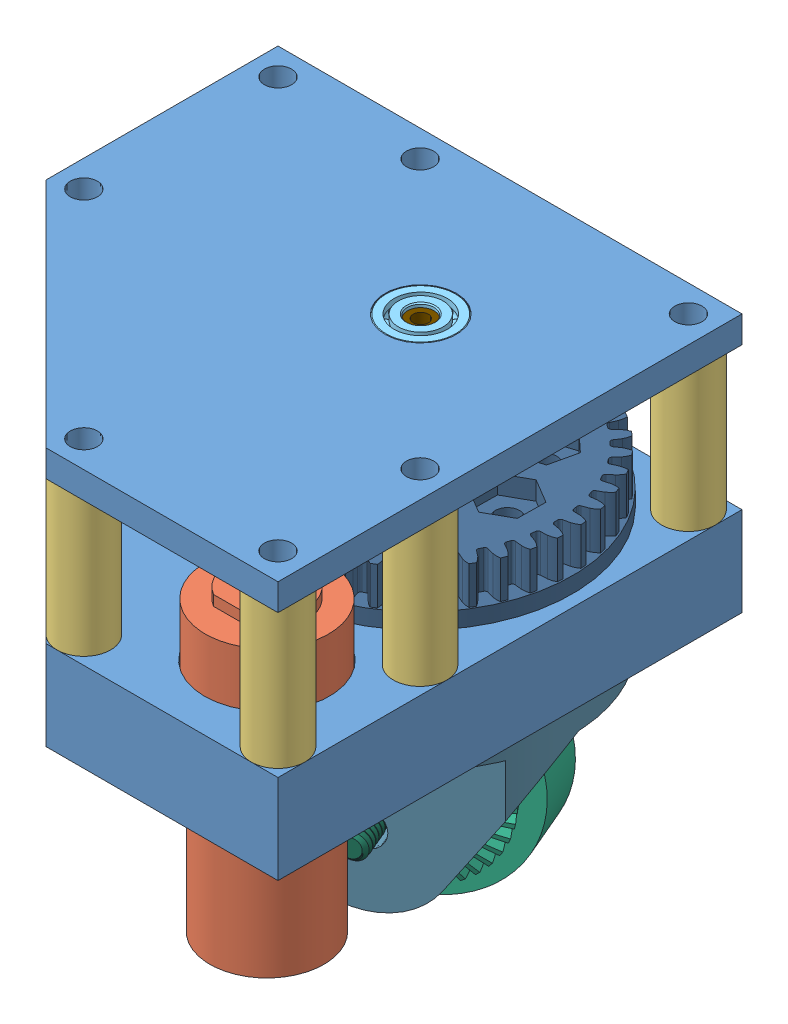
SolidWorks assembly Coaxial-Swerve Test Assem, configuration Default. Lengths in mm.
Overall size (91.34 93.34 91.31).
79 component instances, 21 part files, 31 mates.
Components (placement in the parent):
- Coaxial-Swerve test-1: Coaxial-Swerve test [Default] at origin size (78.17 85.72 76.44) (hidden)
- Middle Container Block-1: Middle Container Block [Default] at (0 47.625 0) size (82.55 15.88 82.55)
- brushless drive motor-1: brushless drive motor [Default] at (9.525 13.7795 36.8902) size (21.95 65.35 21.95)
- brushless drive motor-2: brushless drive motor [Default] at (-36.8902 4.2545 -9.525) size (21.95 65.35 21.95)
- RB Standoff-1: RB Standoff [1000L] at (23.8125 68.2625 -23.8125) size (9.53 25.4 9.53)
- Middle Container Block-2: Middle Container Block [Top] at (0 50.8 0) size (82.55 4.76 82.55)
- RB Standoff-2: RB Standoff [1000L] at (23.8125 68.2625 23.9339) x (0.982082 0 -0.188455) z (0.188455 0 0.982082) size (9.53 25.4 9.53)
- RB Standoff-3: RB Standoff [1000L] at (23.8125 68.2625 49.2125) x (0.918365 0 -0.395734) z (0.395734 0 0.918365) size (9.53 25.4 9.53)
- RB Standoff-4: RB Standoff [1000L] at (-10.7273 68.2625 49.2125) x (0.8 0 -0.6) z (0.6 0 0.8) size (9.53 25.4 9.53)
- RB Standoff-5: RB Standoff [1000L] at (-49.2125 68.2625 10.7273) x (0.63358 0 -0.773678) z (0.773678 0 0.63358) size (9.53 25.4 9.53)
- RB Standoff-6: RB Standoff [1000L] at (-49.2125 68.2625 -23.8125) x (0.443629 0 -0.896211) z (0.896211 0 0.443629) size (9.53 25.4 9.53)
- RB Standoff-7: RB Standoff [1000L] at (-23.9339 68.2625 -23.8125) x (0.263225 0 -0.964735) z (0.964735 0 0.263225) size (9.53 25.4 9.53)
- Coaxial-Swerve Inner Modual Test Assem-1: Coaxial-Swerve Inner Modual Test Assem [Default] at (0 19.05 0) x (-0.393232 0 -0.919439) z (0.919439 0 -0.393232) size (53.98 92.63 53.98)
  - Coaxial-Swerve test-1: Coaxial-Swerve test [Default] at origin size (78.17 85.72 76.44) (hidden)
  - 57155K352_Stainless Steel Ball Bearing-1: 57155K352_Stainless Steel Ball Bearing [57155K352] at (-12.7 7.6375 0) x (1 0 0) z (0 -1 0) size (7.94 7.94 2.78)
  - 60355K502_Ball Bearing-1: 60355K502_Ball Bearing [60355K502] at (-12.7 39.0049 0) x (1 0 0) z (0 -1 0) size (12.7 12.7 3.97)
  - wheel bevel gear-2: wheel bevel gear [Hub and Gear] at (-5.2165 0 0) x (-1 0 0) z (0 -0.800175 0.599767) size (17.39 32.09 32.09)
  - wheel bevel pinion-2: wheel bevel pinion [Inch - Straight bevel pinion 32DP15PT 40GT 20PA .25FW ---15O3H.063MD0.1875N] at (-12.7 16.1735 0) x (0 -1 0) z (0.960661 0 -0.277724) size (7.15 13.7 13.78)
  - Inside Powered Gear-1: Inside Powered Gear [Default] at (-12.7 28.575 0) x (-0.277724 0 -0.960661) z (0 1 0) size (14.29 14.36 13.21)
  - Inside Powering Pinion-1: Inside Powering Pinion [Default] at (0 28.575 0) x (-0.686506 0 0.727124) z (0 1 0) size (14.29 14.36 24.33)
  - Swivel Base Gear-1: Swivel Base Gear [Default] at (0 41.783 0) x (0 0 1) z (0 1 0) size (53.98 53.98 14.13)
  - 60355K503_Ball Bearing (1)-1: 60355K503_Ball Bearing (1) [60355K503] at (0 44.0563 0) x (1 0 0) z (0 -1 0) size (15.88 15.88 4.98)
  - Above Driven Pully-1: Above Driven Pully [Default] at (0 56.515 0) x (0.972961 0 0.23097) z (-0.23097 0 0.972961) size (28.62 10.01 28.62)
  - 9613K15_Wear-Resistant Nylon Balls-1: 9613K15_Wear-Resistant Nylon Balls [9613K15] at (-23.1902 20.3835 0) x (0.958311 0.024656 0.284661) z (-0.285108 0.016955 0.958346) size (4.76 4.76 4.76)
  - 9613K15_Wear-Resistant Nylon Balls-2: 9613K15_Wear-Resistant Nylon Balls [9613K15] at (-23.1902 36.7665 0) size (4.76 4.76 4.76)
  - 9613K15_Wear-Resistant Nylon Balls-3: 9613K15_Wear-Resistant Nylon Balls [9613K15] at (-22.0552 36.7665 7.1662) x (0.951057 0 -0.309017) z (0.309017 0 0.951057) size (4.76 4.76 4.76)
  - 9613K15_Wear-Resistant Nylon Balls-4: 9613K15_Wear-Resistant Nylon Balls [9613K15] at (-18.7613 36.7665 13.6309) x (0.809017 0 -0.587785) z (0.587785 0 0.809017) size (4.76 4.76 4.76)
  - 9613K15_Wear-Resistant Nylon Balls-5: 9613K15_Wear-Resistant Nylon Balls [9613K15] at (-13.6309 36.7665 18.7613) x (0.587785 0 -0.809017) z (0.809017 0 0.587785) size (4.76 4.76 4.76)
  - 9613K15_Wear-Resistant Nylon Balls-6: 9613K15_Wear-Resistant Nylon Balls [9613K15] at (-7.1662 36.7665 22.0552) x (0.309017 0 -0.951057) z (0.951057 0 0.309017) size (4.76 4.76 4.76)
  - 9613K15_Wear-Resistant Nylon Balls-7: 9613K15_Wear-Resistant Nylon Balls [9613K15] at (0 36.7665 23.1902) x (0 0 -1) z (1 0 0) size (4.76 4.76 4.76)
  - 9613K15_Wear-Resistant Nylon Balls-8: 9613K15_Wear-Resistant Nylon Balls [9613K15] at (7.1662 36.7665 22.0552) x (-0.309017 0 -0.951057) z (0.951057 0 -0.309017) size (4.76 4.76 4.76)
  - 9613K15_Wear-Resistant Nylon Balls-9: 9613K15_Wear-Resistant Nylon Balls [9613K15] at (13.6309 36.7665 18.7613) x (-0.587785 0 -0.809017) z (0.809017 0 -0.587785) size (4.76 4.76 4.76)
  - 9613K15_Wear-Resistant Nylon Balls-10: 9613K15_Wear-Resistant Nylon Balls [9613K15] at (18.7613 36.7665 13.6309) x (-0.809017 0 -0.587785) z (0.587785 0 -0.809017) size (4.76 4.76 4.76)
  - 9613K15_Wear-Resistant Nylon Balls-11: 9613K15_Wear-Resistant Nylon Balls [9613K15] at (22.0552 36.7665 7.1662) x (-0.951057 0 -0.309017) z (0.309017 0 -0.951057) size (4.76 4.76 4.76)
  - 9613K15_Wear-Resistant Nylon Balls-12: 9613K15_Wear-Resistant Nylon Balls [9613K15] at (23.1902 36.7665 0) x (-1 0 0) z (0 0 -1) size (4.76 4.76 4.76)
  - 9613K15_Wear-Resistant Nylon Balls-13: 9613K15_Wear-Resistant Nylon Balls [9613K15] at (22.0552 36.7665 -7.1662) x (-0.951057 0 0.309017) z (-0.309017 0 -0.951057) size (4.76 4.76 4.76)
  - 9613K15_Wear-Resistant Nylon Balls-14: 9613K15_Wear-Resistant Nylon Balls [9613K15] at (18.7613 36.7665 -13.6309) x (-0.809017 0 0.587785) z (-0.587785 0 -0.809017) size (4.76 4.76 4.76)
  - 9613K15_Wear-Resistant Nylon Balls-15: 9613K15_Wear-Resistant Nylon Balls [9613K15] at (13.6309 36.7665 -18.7613) x (-0.587785 0 0.809017) z (-0.809017 0 -0.587785) size (4.76 4.76 4.76)
  - 9613K15_Wear-Resistant Nylon Balls-16: 9613K15_Wear-Resistant Nylon Balls [9613K15] at (7.1662 36.7665 -22.0552) x (-0.309017 0 0.951057) z (-0.951057 0 -0.309017) size (4.76 4.76 4.76)
  - 9613K15_Wear-Resistant Nylon Balls-17: 9613K15_Wear-Resistant Nylon Balls [9613K15] at (0 36.7665 -23.1902) x (0 0 1) z (-1 0 0) size (4.76 4.76 4.76)
  - 9613K15_Wear-Resistant Nylon Balls-18: 9613K15_Wear-Resistant Nylon Balls [9613K15] at (-7.1662 36.7665 -22.0552) x (0.309017 0 0.951057) z (-0.951057 0 0.309017) size (4.76 4.76 4.76)
  - 9613K15_Wear-Resistant Nylon Balls-19: 9613K15_Wear-Resistant Nylon Balls [9613K15] at (-13.6309 36.7665 -18.7613) x (0.587785 0 0.809017) z (-0.809017 0 0.587785) size (4.76 4.76 4.76)
  - 9613K15_Wear-Resistant Nylon Balls-20: 9613K15_Wear-Resistant Nylon Balls [9613K15] at (-18.7613 36.7665 -13.6309) x (0.809017 0 0.587785) z (-0.587785 0 0.809017) size (4.76 4.76 4.76)
  - 9613K15_Wear-Resistant Nylon Balls-21: 9613K15_Wear-Resistant Nylon Balls [9613K15] at (-22.0552 36.7665 -7.1662) x (0.951057 0 0.309017) z (-0.309017 0 0.951057) size (4.76 4.76 4.76)
  - 9613K15_Wear-Resistant Nylon Balls-22: 9613K15_Wear-Resistant Nylon Balls [9613K15] at (-22.0552 20.3835 7.1662) x (0.999373 0.024656 -0.025406) z (0.024992 0.016955 0.999544) size (4.76 4.76 4.76)
  - 9613K15_Wear-Resistant Nylon Balls-23: 9613K15_Wear-Resistant Nylon Balls [9613K15] at (-18.7613 20.3835 13.6309) x (0.94261 0.024656 -0.332985) z (0.332645 0.016955 0.9429) size (4.76 4.76 4.76)
  - 9613K15_Wear-Resistant Nylon Balls-24: 9613K15_Wear-Resistant Nylon Balls [9613K15] at (-13.6309 20.3835 18.7613) x (0.793577 0.024656 -0.60797) z (0.607736 0.016955 0.793958) size (4.76 4.76 4.76)
  - 9613K15_Wear-Resistant Nylon Balls-25: 9613K15_Wear-Resistant Nylon Balls [9613K15] at (-7.1662 20.3835 22.0552) x (0.566863 0.024656 -0.823443) z (0.823338 0.016955 0.567298) size (4.76 4.76 4.76)
  - 9613K15_Wear-Resistant Nylon Balls-26: 9613K15_Wear-Resistant Nylon Balls [9613K15] at (0 20.3835 23.1902) x (0.284661 0.024656 -0.958311) z (0.958346 0.016955 0.285108) size (4.76 4.76 4.76)
  - 9613K15_Wear-Resistant Nylon Balls-27: 9613K15_Wear-Resistant Nylon Balls [9613K15] at (7.1662 20.3835 22.0552) x (-0.025406 0.024656 -0.999373) z (0.999544 0.016955 -0.024992) size (4.76 4.76 4.76)
  - 9613K15_Wear-Resistant Nylon Balls-28: 9613K15_Wear-Resistant Nylon Balls [9613K15] at (13.6309 20.3835 18.7613) x (-0.332985 0.024656 -0.94261) z (0.9429 0.016955 -0.332645) size (4.76 4.76 4.76)
  - 9613K15_Wear-Resistant Nylon Balls-29: 9613K15_Wear-Resistant Nylon Balls [9613K15] at (18.7613 20.3835 13.6309) x (-0.60797 0.024656 -0.793577) z (0.793958 0.016955 -0.607736) size (4.76 4.76 4.76)
  - 9613K15_Wear-Resistant Nylon Balls-30: 9613K15_Wear-Resistant Nylon Balls [9613K15] at (22.0552 20.3835 7.1662) x (-0.823443 0.024656 -0.566863) z (0.567298 0.016955 -0.823338) size (4.76 4.76 4.76)
  - 9613K15_Wear-Resistant Nylon Balls-31: 9613K15_Wear-Resistant Nylon Balls [9613K15] at (23.1902 20.3835 0) x (-0.958311 0.024656 -0.284661) z (0.285108 0.016955 -0.958346) size (4.76 4.76 4.76)
  - 9613K15_Wear-Resistant Nylon Balls-32: 9613K15_Wear-Resistant Nylon Balls [9613K15] at (22.0552 20.3835 -7.1662) x (-0.999373 0.024656 0.025406) z (-0.024992 0.016955 -0.999544) size (4.76 4.76 4.76)
  - 9613K15_Wear-Resistant Nylon Balls-33: 9613K15_Wear-Resistant Nylon Balls [9613K15] at (18.7613 20.3835 -13.6309) x (-0.94261 0.024656 0.332985) z (-0.332645 0.016955 -0.9429) size (4.76 4.76 4.76)
  - 9613K15_Wear-Resistant Nylon Balls-34: 9613K15_Wear-Resistant Nylon Balls [9613K15] at (13.6309 20.3835 -18.7613) x (-0.793577 0.024656 0.60797) z (-0.607736 0.016955 -0.793958) size (4.76 4.76 4.76)
  - 9613K15_Wear-Resistant Nylon Balls-35: 9613K15_Wear-Resistant Nylon Balls [9613K15] at (7.1662 20.3835 -22.0552) x (-0.566863 0.024656 0.823443) z (-0.823338 0.016955 -0.567298) size (4.76 4.76 4.76)
  - 9613K15_Wear-Resistant Nylon Balls-36: 9613K15_Wear-Resistant Nylon Balls [9613K15] at (0 20.3835 -23.1902) x (-0.284661 0.024656 0.958311) z (-0.958346 0.016955 -0.285108) size (4.76 4.76 4.76)
  - 9613K15_Wear-Resistant Nylon Balls-37: 9613K15_Wear-Resistant Nylon Balls [9613K15] at (-7.1662 20.3835 -22.0552) x (0.025406 0.024656 0.999373) z (-0.999544 0.016955 0.024992) size (4.76 4.76 4.76)
  - 9613K15_Wear-Resistant Nylon Balls-38: 9613K15_Wear-Resistant Nylon Balls [9613K15] at (-13.6309 20.3835 -18.7613) x (0.332985 0.024656 0.94261) z (-0.9429 0.016955 0.332645) size (4.76 4.76 4.76)
  - 9613K15_Wear-Resistant Nylon Balls-39: 9613K15_Wear-Resistant Nylon Balls [9613K15] at (-18.7613 20.3835 -13.6309) x (0.60797 0.024656 0.793577) z (-0.793958 0.016955 0.607736) size (4.76 4.76 4.76)
  - 9613K15_Wear-Resistant Nylon Balls-40: 9613K15_Wear-Resistant Nylon Balls [9613K15] at (-22.0552 20.3835 -7.1662) x (0.823443 0.024656 0.566863) z (-0.567298 0.016955 0.823338) size (4.76 4.76 4.76)
  - Wheel Container-1: Wheel Container [Default] at (0 17.7482 0) size (53.98 32.83 53.98)
  - 60355K503_Ball Bearing (1)-2: 60355K503_Ball Bearing (1) [60355K503] at (5.35 0 0) x (0 -1 0) z (-1 0 0) size (15.88 15.88 4.98)
  - 60355K503_Ball Bearing (1)-3: 60355K503_Ball Bearing (1) [60355K503] at (-5.4285 0 0) x (0 -1 0) z (-1 0 0) size (15.88 15.88 4.98)
  - 91259A544_Alloy Steel Shoulder Screw-1: 91259A544_Alloy Steel Shoulder Screw [91259A544] at (-0.8065 0 0) x (0 -0.924225 -0.381849) z (1 0 0) size (9.53 9.53 46.56)
  - Inner Swerve Spacer-1: Inner Swerve Spacer [Default] at (-6.35 28.575 14.2875) size (6.99 16.89 6.99)
  - Inner Swerve Spacer-2: Inner Swerve Spacer [Default] at (6.35 28.575 14.2875) x (0.982082 0 -0.188455) z (0.188455 0 0.982082) size (6.99 16.89 6.99)
  - Inner Swerve Spacer-3: Inner Swerve Spacer [Default] at (14.2875 28.575 6.35) x (0.918365 0 -0.395734) z (0.395734 0 0.918365) size (6.99 16.89 6.99)
  - Inner Swerve Spacer-4: Inner Swerve Spacer [Default] at (14.2875 28.575 -6.35) x (0.8 0 -0.6) z (0.6 0 0.8) size (6.99 16.89 6.99)
  - Inner Swerve Spacer-5: Inner Swerve Spacer [Default] at (6.35 28.575 -14.2875) x (0.63358 0 -0.773678) z (0.773678 0 0.63358) size (6.99 16.89 6.99)
  - Inner Swerve Spacer-6: Inner Swerve Spacer [Default] at (-6.35 28.575 -14.2875) x (0.325934 0 -0.945392) z (0.945392 0 0.325934) size (6.99 16.89 6.99)
  - wheel bevel gear-3: wheel bevel gear [Tire] at (-5.2165 0 0) x (-1 0 0) z (0 -0.800175 0.599767) size (9.53 38.1 38.1)
  - Swerve Stage 3 Drive Shaft-1: Swerve Stage 3 Drive Shaft [Default] at (-12.7 23.0219 0) x (-0.970819 0 -0.239814) z (0.239814 0 -0.970819) size (5.5 34.34 4.76)
  - Swerve Stage 2 Drive Shaft-1: Swerve Stage 2 Drive Shaft [Default] at (0 44.0944 0) x (0.686506 0 -0.727124) z (0.727124 0 0.686506) size (5.5 40.56 4.76)
  - Sput to Bevel Gear Spacer-1: Sput to Bevel Gear Spacer [Default] at (-12.7 19.9963 0) size (6.99 7.65 6.99)
  - Inside Pullies Spacer-1: Inside Pullies Spacer [Default] at (0 49.6316 0) size (8.26 6.17 8.26)
- 60355K502_Ball Bearing-3: 60355K502_Ball Bearing [60355K502] at (0 83.7406 0) x (1 0 0) z (0 -1 0) size (12.7 12.7 3.97)
Mates (geometry in assembly coordinates):
- Coincident1: coincident aligned: plane of Coaxial-Swerve test-1 through (0 0 0) normal (0 0 1)
- Coincident2: coincident aligned: plane of Coaxial-Swerve test-1 through (0 0 0) normal (0 1 0)
- Coincident3: coincident aligned: plane of Coaxial-Swerve test-1 through (0 0 0) normal (1 0 0)
- Coincident39: coincident aligned: plane of Middle Container Block-1 through (0 47.625 0) normal (0 0 1)
- Coincident40: coincident aligned: plane of Middle Container Block-1 through (0 47.625 0) normal (1 0 0)
- Coincident48: coincident anti-aligned: circle of Coaxial-Swerve test-1; cylinder of brushless drive motor-1 through (9.525 65.0875 36.8902) axis (0 -1 0) radius 10.9728
- Coincident49: coincident anti-aligned: circle of Coaxial-Swerve test-1; cylinder of brushless drive motor-2 through (-36.8902 55.5625 -9.525) axis (0 -1 0) radius 10.9728
- Coincident50: coincident aligned: plane of Middle Container Block-1 through (0 55.5625 26.9875) normal (0 1 0); plane of brushless drive motor-2 through (-36.8902 55.5625 -9.525) normal (0 1 0)
- Distance1: distance = 9.525 mm aligned: plane of brushless drive motor-1 through (9.525 65.0875 36.8902) normal (0 1 0); plane of Middle Container Block-1 through (0 55.5625 26.9875) normal (0 1 0)
- Distance2: distance = 25.4 mm anti-aligned: plane of Middle Container Block-1 through (0 55.5625 26.9875) normal (0 1 0); plane of Middle Container Block-2 through (0 80.9625 0) normal (0 -1 0)
- Concentric30: concentric aligned: cylinder of Middle Container Block-1 through (-49.2125 39.6875 -23.8125) axis (0 1 0) radius 2.4257; cylinder of Middle Container Block-2 through (-49.2125 42.8625 -23.8125) axis (0 1 0) radius 2.4257
- Concentric31: concentric aligned: cylinder of Middle Container Block-1 through (23.8125 39.6875 49.2125) axis (0 1 0) radius 2.4257; cylinder of Middle Container Block-2 through (23.8125 42.8625 49.2125) axis (0 1 0) radius 2.4257
- Coincident51: coincident anti-aligned: plane of RB Standoff-1 through (23.8125 80.9625 -23.8125) normal (0 1 0); plane of Middle Container Block-2 through (0 80.9625 0) normal (0 -1 0)
- Coincident52: coincident anti-aligned: plane of Middle Container Block-2 through (0 80.9625 0) normal (0 -1 0); plane of RB Standoff-2 through (23.8125 80.9625 23.9339) normal (0 1 0)
- Coincident53: coincident anti-aligned: plane of Middle Container Block-2 through (0 80.9625 0) normal (0 -1 0); plane of RB Standoff-3 through (23.8125 80.9625 49.2125) normal (0 1 0)
- Coincident54: coincident anti-aligned: plane of Middle Container Block-2 through (0 80.9625 0) normal (0 -1 0); plane of RB Standoff-4 through (-10.7273 80.9625 49.2125) normal (0 1 0)
- Coincident55: coincident anti-aligned: plane of Middle Container Block-2 through (0 80.9625 0) normal (0 -1 0); plane of RB Standoff-5 through (-49.2125 80.9625 10.7273) normal (0 1 0)
- Coincident56: coincident anti-aligned: plane of Middle Container Block-2 through (0 80.9625 0) normal (0 -1 0); plane of RB Standoff-6 through (-49.2125 80.9625 -23.8125) normal (0 1 0)
- Coincident57: coincident anti-aligned: plane of Middle Container Block-2 through (0 80.9625 0) normal (0 -1 0); plane of RB Standoff-7 through (-23.9339 80.9625 -23.8125) normal (0 1 0)
- Concentric32: concentric anti-aligned: cylinder of RB Standoff-1 through (23.8125 80.9625 -23.8125) axis (0 -1 0) radius 4.7625; cylinder of Middle Container Block-2 through (23.8125 42.8625 -23.8125) axis (0 1 0) radius 2.4257
- Concentric33: concentric anti-aligned: cylinder of Middle Container Block-2 through (23.8125 42.8625 23.9339) axis (0 1 0) radius 2.4257; cylinder of RB Standoff-2 through (23.8125 80.9625 23.9339) axis (0 -1 0) radius 4.7625
- Concentric34: concentric anti-aligned: cylinder of Middle Container Block-2 through (23.8125 42.8625 49.2125) axis (0 1 0) radius 2.4257; cylinder of RB Standoff-3 through (23.8125 80.9625 49.2125) axis (0 -1 0) radius 4.7625
- Concentric35: concentric anti-aligned: cylinder of Middle Container Block-2 through (-10.7273 42.8625 49.2125) axis (0 1 0) radius 2.4257; cylinder of RB Standoff-4 through (-10.7273 80.9625 49.2125) axis (0 -1 0) radius 4.7625
- Concentric36: concentric anti-aligned: cylinder of Middle Container Block-2 through (-49.2125 42.8625 10.7273) axis (0 1 0) radius 2.4257; cylinder of RB Standoff-5 through (-49.2125 80.9625 10.7273) axis (0 -1 0) radius 4.7625
- Concentric37: concentric anti-aligned: cylinder of Middle Container Block-2 through (-49.2125 42.8625 -23.8125) axis (0 1 0) radius 2.4257; cylinder of RB Standoff-6 through (-49.2125 80.9625 -23.8125) axis (0 -1 0) radius 4.7625
- Concentric38: concentric anti-aligned: cylinder of Middle Container Block-2 through (-23.9339 42.8625 -23.8125) axis (0 1 0) radius 2.4257; cylinder of RB Standoff-7 through (-23.9339 80.9625 -23.8125) axis (0 -1 0) radius 4.7625
- Distance3: distance = 85.725 mm aligned: plane of Middle Container Block-2 through (0 85.725 0) normal (0 1 0)
- Width1: width aligned: plane of Coaxial-Swerve Inner Modual Test Assem-1/Wheel Container-1 through (10.0617 39.1795 23.5258) normal (0 1 0); plane of Middle Container Block-1 through (0 56.0705 0) normal (0 -1 0); plane of Coaxial-Swerve Inner Modual Test Assem-1/Swivel Base Gear-1 through (0 55.5625 26.9875) normal (0 1 0); plane of Middle Container Block-1 through (0 39.6875 26.9875) normal (0 -1 0)
- Concentric39: concentric aligned: cylinder of Middle Container Block-1 through (0 47.625 0) axis (0 -1 0) radius 20.6375; cylinder of Coaxial-Swerve Inner Modual Test Assem-1/Swivel Base Gear-1 through (0 58.8645 0) axis (0 -1 0) radius 26.9875
- Concentric40: concentric aligned: cylinder of Middle Container Block-2 through (0 85.725 0) axis (0 -1 0) radius 6.35; cylinder of 60355K502_Ball Bearing-3 through (0 81.7563 0) axis (0 -1 0) radius 6.35
- Coincident58: coincident aligned: plane of Middle Container Block-2 through (0 85.725 0) normal (0 1 0); plane of 60355K502_Ball Bearing-3 through (0 85.725 6.1516) normal (0 1 0)
